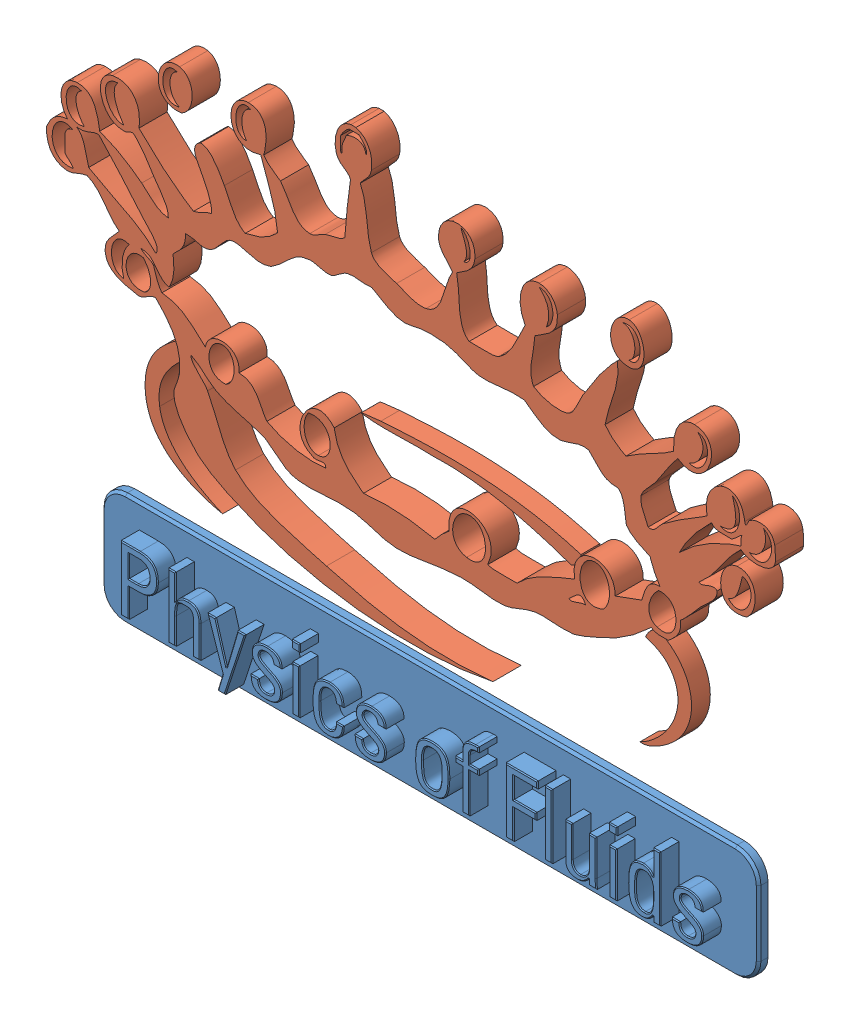
SolidWorks assembly PoF_assy, configuration Default. Lengths in mm.
Overall size (155.42 120.25 6).
2 component instances, 2 part files, 6 mates.
Components (placement in the parent):
- Physics_of_Fluids-1: Physics_of_Fluids [Default] at (0 0 2) size (140 24 6)
- PoF_logo-1: PoF_logo [Default] at (-15.889 24 0) size (155.42 90.13 6)
Mates (geometry in assembly coordinates):
- Coincident1: coincident anti-aligned: plane of PoF_logo-1 through (-15.889 24 0) normal (0 0 -1)
- Distance1: distance = 24 mm aligned: plane of Physics_of_Fluids-1 through (0 0 2) normal (0 1 0); plane of PoF_logo-1 through (-15.889 24 0) normal (0 1 0)
- Distance2: distance = 15.889 mm aligned: plane of Physics_of_Fluids-1 through (0 0 2) normal (1 0 0); plane of PoF_logo-1 through (-15.889 24 0) normal (1 0 0)
- Coincident2: coincident anti-aligned: plane of Physics_of_Fluids-1 through (127.0017 -0.1337 0) normal (0 0 -1)
- Coincident3: coincident aligned: plane of Physics_of_Fluids-1 through (0 0 2) normal (0 1 0)
- Coincident4: coincident aligned: plane of Physics_of_Fluids-1 through (0 0 2) normal (1 0 0)
